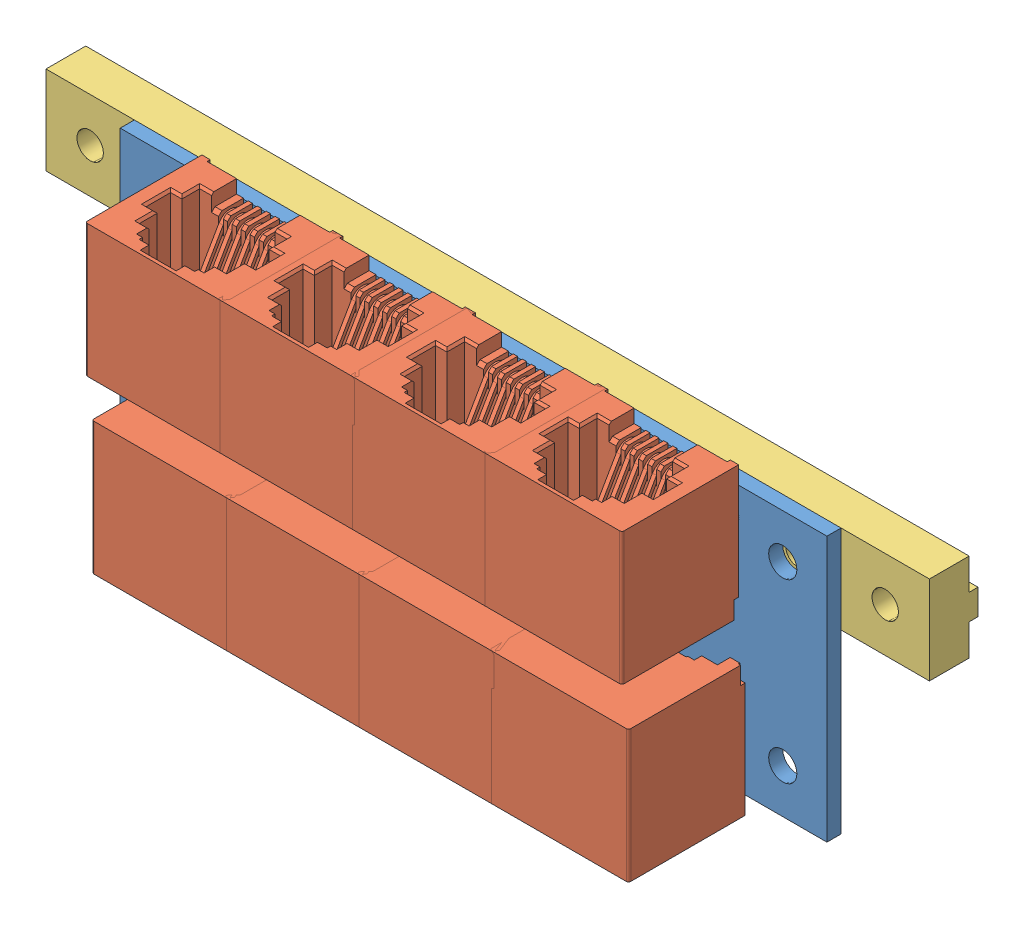
SolidWorks assembly Assem1, configuration Default. Lengths in mm.
Overall size (100 34 20.31).
11 component instances, 3 part files, 3 mates.
Components (placement in the parent):
- ICD3Board-1: ICD3Board [Default] at (-13.2292 0.5918 0.7496) size (80 34 16.36)
  - ICD3BoardSupport-1: ICD3BoardSupport [Default] at (29.1948 40.7842 61.6139) size (80 30 1.6)
  - User Library-RJ11-6PM-1: User Library-RJ11-6PM [Default] at (7.0688 31.2772 69.8179) x (1 0 0) z (0 -1 0) size (15.88 16.36 14.99)
  - User Library-RJ11-6PM-2: User Library-RJ11-6PM [Default] at (22.0688 31.2772 69.8179) x (1 0 0) z (0 -1 0) size (15.88 16.36 14.99)
  - User Library-RJ11-6PM-3: User Library-RJ11-6PM [Default] at (37.0688 31.2772 69.8179) x (1 0 0) z (0 -1 0) size (15.88 16.36 14.99)
  - User Library-RJ11-6PM-4: User Library-RJ11-6PM [Default] at (52.0688 31.2772 69.8179) x (1 0 0) z (0 -1 0) size (15.88 16.36 14.99)
  - User Library-RJ11-6PM-10: User Library-RJ11-6PM [Default] at (51.3208 50.2912 69.8179) x (-1 0 0) z (0 1 0) size (15.88 16.36 14.99)
  - User Library-RJ11-6PM-11: User Library-RJ11-6PM [Default] at (36.3208 50.2912 69.8179) x (-1 0 0) z (0 1 0) size (15.88 16.36 14.99)
  - User Library-RJ11-6PM-12: User Library-RJ11-6PM [Default] at (21.3208 50.2912 69.8179) x (-1 0 0) z (0 1 0) size (15.88 16.36 14.99)
  - User Library-RJ11-6PM-13: User Library-RJ11-6PM [Default] at (6.3208 50.2912 69.8179) x (-1 0 0) z (0 1 0) size (15.88 16.36 14.99)
- ICD3BoardMakerBeamSupport-1: ICD3BoardMakerBeamSupport [Default] at (65.9655 51.376 62.3635) x (0 -1 0) z (-1 0 0) size (10 5.5 100)
Mates (geometry in assembly coordinates):
- Concentric1: concentric: cylinder of ICD3Board-1/ICD3BoardSupport-1 through (50.9655 51.376 63.9635) axis (0 0 -1) radius 1.6; cylinder of ICD3BoardMakerBeamSupport-1 through (50.9655 51.376 56.8635) axis (0 0 1) radius 1.25
- Coincident1: coincident: plane of ICD3Board-1/ICD3BoardSupport-1 through (15.9655 41.376 62.3635) normal (0 0 -1); plane of ICD3BoardMakerBeamSupport-1 through (-33.6521 41.8969 62.3635) normal (0 0 1)
- Concentric2: concentric anti-aligned: cylinder of ICD3Board-1/ICD3BoardSupport-1 through (-19.0345 51.376 63.9635) axis (0 0 -1) radius 1.6; cylinder of ICD3BoardMakerBeamSupport-1 through (-19.0345 51.376 56.8635) axis (0 0 1) radius 1.25
